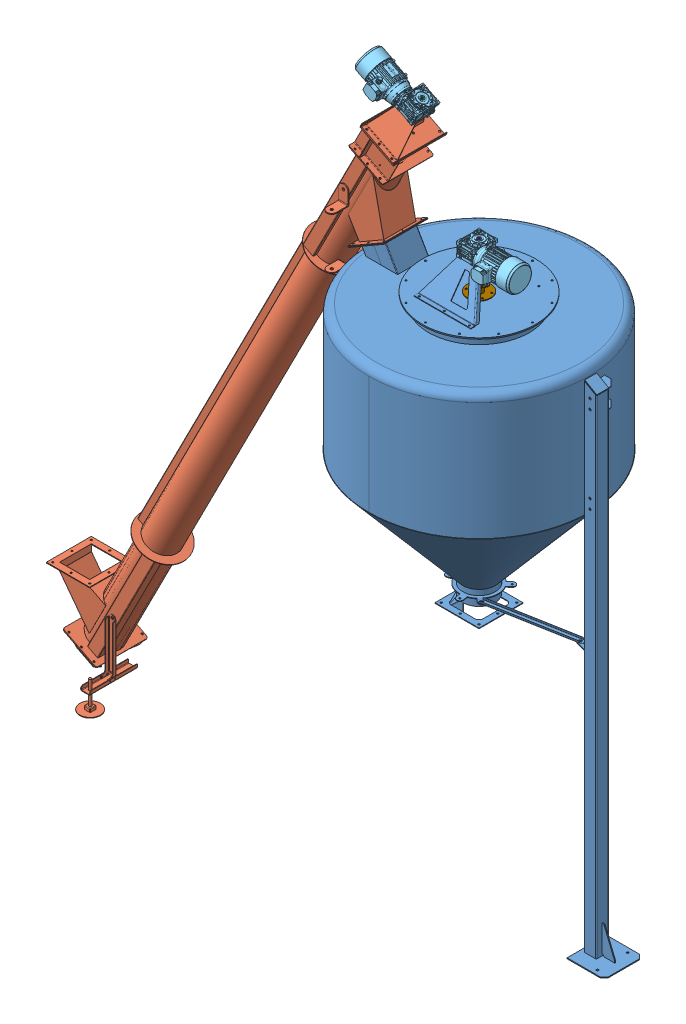
SolidWorks assembly Собираемость ШН+ЕМК ЗАГР, configuration _00. Lengths in mm.
Overall size (3529.98 4401.95 1403.05).
16 component instances, 14 part files, 35 mates.
Components (placement in the parent):
- Емкость Разгр СВД-1: Емкость Разгр СВД [_00] at origin size (1682.69 3474.3 1403.05)
- Шнек Шнек РАЗГ СВД-1: Шнек Шнек РАЗГ СВД [_00] at (-2375.6474 197.619 0) size (2261.6 4104.57 500)
- UCF205-1: UCF205 [_00] at (-2445.5619 60.404 0) x (-0.45399 -0.891007 0) z (0 0 1) size (35.7 95 95) (hidden)
- UCF205-2: UCF205 [_00] at (-485.2309 3907.7702 0) x (-0.45399 -0.891007 0) z (0 0 1) size (35.7 95 95)
- Спираль РАЗГ СВД-1: Спираль РАЗГ СВД [_00] at (-2462.8135 26.5458 0) x (0.45399 0.891007 0) z (0 0 1) size (4841.57 194.01 194.56)
- Редуктор-1: Редуктор [_00] at (-530.0231 3819.8606 0) x (-0.45399 -0.891007 0) z (0 0 1) size (160.29 372.5 231.5)
- 2.377.06.00.01_Вал-1: 2.377.06.00.01_Вал [_00] at (-359.2486 4155.0245 0) x (-0.45399 -0.891007 0) z (0 0 1) size (160 25 25)
- 2.377.06.00.02_Втулка-1: 2.377.06.00.02_Втулка [_00] at (-477.0591 3923.8083 0) x (0.45399 0.891007 0) z (0 0 1) size (127 34 34)
- Редуктор-2: Редуктор [_00] at (0 3843.6632 0) x (0 1 0) z (0 0 1) size (160.29 372.5 231.5)
- 2.377.06.00.03_Вал-1: 2.377.06.00.03_Вал [_00] at (0 3559.5 0) x (0 -1 0) z (-0.877345 0 0.479861) size (360 25 25)
- Сальник ДЕТ-1: Сальник ДЕТ [_00] at (15.0304 3266 705.4055) x (0 1 0) z (-0.506034 0 0.862514) size (88 150 150)
- 2.377.06.00.04_Труба-1: 2.377.06.00.04_Труба [_00] at (0 1662 0) x (0.479861 0 0.877345) z (-0.877345 0 0.479861) size (30 1585 30)
- 2.377.06.00.05_Втулка-1: 2.377.06.00.05_Втулка [_00] at (0 1652 0) size (30 30 30)
- 2.377.06.00.06_Штырь-1: 2.377.06.00.06_Штырь [_00] at (175.4689 1867 -95.9722) x (0.479861 0 0.877345) z (-0.877345 0 0.479861) size (12 12 400)
- 2.377.06.00.07_Штырь-1: 2.377.06.00.07_Штырь [_00] at (-50.3854 1747 -92.1212) x (0.877345 0 -0.479861) z (0.479861 0 0.877345) size (12 12 210)
- Винт М6х16 DIN7991-1: Винт М6х16 DIN7991 [По умолчанию] at (-2439.5238 72.2544 17.8) x (0 0 1) z (-1 0 0) size (16 13.4 13.4)
Mates (geometry in assembly coordinates):
- Совпадение1: coincident anti-aligned: plane of Емкость Разгр СВД-1 through (-692 3237.7 140) normal (-0.5 0.866025 0); plane of Шнек Шнек РАЗГ СВД-1 through (-692 3237.7 140) normal (0.5 -0.866025 0)
- Концентричный1: concentric anti-aligned: cylinder of Емкость Разгр СВД-1 through (-479.1539 3349.0397 120) axis (-0.5 0.866025 0) radius 5.5; cylinder of Шнек Шнек РАЗГ СВД-1 through (-487.1539 3362.8962 120) axis (0.5 -0.866025 0) radius 5.5
- Концентричный2: concentric anti-aligned: cylinder of Емкость Разгр СВД-1 through (-669.6795 3239.0397 120) axis (-0.5 0.866025 0) radius 5.5; cylinder of Шнек Шнек РАЗГ СВД-1 through (-677.6795 3252.8962 120) axis (0.5 -0.866025 0) radius 5.5
- Совпадение4: coincident anti-aligned: plane of Шнек Шнек РАЗГ СВД-1 through (-2338.6411 5.9252 -60) normal (-0.45399 -0.891007 0); plane of UCF205-1 through (-2487.8847 81.9686 47.5) normal (0.45399 0.891007 0)
- Концентричный5: concentric aligned: cylinder of Шнек Шнек РАЗГ СВД-1 through (-2443.2919 64.8591 0) axis (-0.45399 -0.891007 0) radius 25; cylinder of UCF205-1 through (-2461.7694 28.5951 0) axis (-0.45399 -0.891007 0) radius 12.5
- Концентричный6: concentric anti-aligned: cylinder of Шнек Шнек РАЗГ СВД-1 through (-2474.4772 80.7487 -35) axis (-0.45399 -0.891007 0) radius 5.5; cylinder of UCF205-1 through (-2483.103 63.8196 -35) axis (0.45399 0.891007 0) radius 6
- Концентричный7: concentric anti-aligned: cylinder of UCF205-1 through (-2461.7694 28.5951 0) axis (-0.45399 -0.891007 0) radius 12.5; cylinder of Спираль РАЗГ СВД-1 through (-2357.4877 233.2593 0) axis (0.45399 0.891007 0) radius 12.5
- Совпадение5: coincident anti-aligned: plane of UCF205-1 through (-2462.8966 67.3286 -18.25) normal (0.45399 0.891007 0); plane of Спираль РАЗГ СВД-1 through (-2457.4713 64.5642 0) normal (-0.45399 -0.891007 0)
- Совпадение6: coincident aligned: plane of Шнек Шнек РАЗГ СВД-1 through (-76.3155 3910.4147 0) normal (0.45399 0.891007 0); plane of Редуктор-1 through (-354.8665 4052.3435 -50.5206) normal (0.45399 0.891007 0)
- Концентричный8: concentric anti-aligned: cylinder of Шнек Шнек РАЗГ СВД-1 through (-403.5126 4068.1514 0) axis (0.45399 0.891007 0) radius 35; cylinder of Редуктор-1 through (-399.8807 4075.2794 0) axis (-0.45399 -0.891007 0) radius 35
- Концентричный9: concentric anti-aligned: cylinder of Шнек Шнек РАЗГ СВД-1 through (-430.2892 4081.7947 30.052) axis (0.45399 0.891007 0) radius 3.5; cylinder of Редуктор-1 through (-426.3501 4089.5255 30.052) axis (-0.45399 -0.891007 0) radius 3.3235
- Концентричный10: concentric aligned: cylinder of Редуктор-1 through (-401.0157 4073.0519 0) axis (0.45399 0.891007 0) radius 12.5; cylinder of 2.377.06.00.01_Вал-1 through (-401.0157 4073.0519 0) axis (0.45399 0.891007 0) radius 12.5
- Совпадение8: coincident aligned: plane of Редуктор-1 through (-418.8367 4082.1322 -20.001) normal (-0.45399 -0.891007 0); plane of 2.377.06.00.01_Вал-1 through (-401.0157 4073.0519 0) normal (-0.45399 -0.891007 0)
- Перпендикулярность2: perpendicular: plane of Спираль РАЗГ СВД-1 through (-485.8185 3918.7317 -97.2781) normal (0.891007 -0.45399 0); plane of 2.377.06.00.01_Вал-1 through (-439.5773 4030.4109 5.5) normal (0 0 -1)
- Совпадение9: coincident aligned: plane of Емкость Разгр СВД-1 through (180 3470 0) normal (0 1 0); plane of Редуктор-2 through (50.446 3470 -50.446) normal (0 1 0)
- Концентричный14: concentric aligned: cylinder of Емкость Разгр СВД-1 through (0 3463.2 0) axis (0 1 0) radius 35.5; cylinder of Редуктор-2 through (0 3557 0) axis (0 1 0) radius 35
- Концентричный15: concentric aligned: cylinder of Емкость Разгр СВД-1 through (30.052 3463.2 30.052) axis (0 1 0) radius 4.5; cylinder of Редуктор-2 through (30.052 3556.3235 30.052) axis (0 1 0) radius 3.3235
- Совпадение11: coincident aligned: plane of Редуктор-2 through (20.001 3559.5 -20.001) normal (0 1 0); plane of 2.377.06.00.03_Вал-1 through (0 3559.5 0) normal (0 1 0)
- Концентричный16: concentric aligned: cylinder of Редуктор-2 through (0 3559.5 0) axis (0 -1 0) radius 12.5; cylinder of 2.377.06.00.03_Вал-1 through (0 3510.3507 0) axis (0 -1 0) radius 12.5
- Концентричный17: concentric aligned: cylinder of Емкость Разгр СВД-1 through (0 3266 0) axis (0 -1 0) radius 360; cylinder of Сальник ДЕТ-1 through (0 3482.132 0) axis (0 -1 0) radius 75
- Совпадение13: coincident anti-aligned: plane of Емкость Разгр СВД-1 through (0 3266 0) normal (0 1 0); plane of Сальник ДЕТ-1 through (0 3266 0) normal (0 -1 0)
- Концентричный18: concentric aligned: cylinder of 2.377.06.00.03_Вал-1 through (0 3510.3507 0) axis (0 -1 0) radius 12.5; cylinder of 2.377.06.00.04_Труба-1 through (0 3247 0) axis (0 -1 0) radius 15
- Концентричный19: concentric aligned: cylinder of 2.377.06.00.03_Вал-1 through (10.9668 3232 -5.9983) axis (-0.877345 0 0.479861) radius 5.5; cylinder of 2.377.06.00.04_Труба-1 through (13.1602 3232 -7.1979) axis (-0.877345 0 0.479861) radius 5.5
- Совпадение14: coincident anti-aligned: plane of 2.377.06.00.04_Труба-1 through (0 1662 0) normal (0 -1 0); plane of 2.377.06.00.05_Втулка-1 through (-15 1662 0) normal (0 1 0)
- Концентричный20: concentric anti-aligned: cylinder of 2.377.06.00.04_Труба-1 through (0 3247 0) axis (0 -1 0) radius 15; cylinder of 2.377.06.00.05_Втулка-1 through (0 1682 0) axis (0 1 0) radius 12.5
- Концентричный21: concentric anti-aligned: cylinder of 2.377.06.00.04_Труба-1 through (-7.1979 1747 -13.1602) axis (0.479861 0 0.877345) radius 6; cylinder of 2.377.06.00.07_Штырь-1 through (50.3854 1747 92.1212) axis (-0.479861 0 -0.877345) radius 6
- Концентричный22: concentric anti-aligned: cylinder of 2.377.06.00.04_Труба-1 through (13.1602 1867 -7.1979) axis (-0.877345 0 0.479861) radius 6; cylinder of 2.377.06.00.06_Штырь-1 through (-175.4689 1867 95.9722) axis (0.877345 0 -0.479861) radius 6
- Симметричный1: symmetric aligned: plane of 2.377.06.00.04_Труба-1 through (0 1662 0) normal (-0.877345 0 0.479861); plane of 2.377.06.00.06_Штырь-1 through (-175.4689 1867 95.9722) normal (-0.877345 0 0.479861); plane of 2.377.06.00.06_Штырь-1 through (175.4689 1867 -95.9722) normal (0.877345 0 -0.479861)
- Симметричный2: symmetric aligned: plane of 2.377.06.00.04_Труба-1 through (0 1662 0) normal (0.479861 0 0.877345); plane of 2.377.06.00.07_Штырь-1 through (50.3854 1747 92.1212) normal (0.479861 0 0.877345); plane of 2.377.06.00.07_Штырь-1 through (-50.3854 1747 -92.1212) normal (-0.479861 0 -0.877345)
- Совпадение15: coincident aligned: cone of Спираль РАЗГ СВД-1 through (-2439.5238 72.2544 14.25) axis (0 0 -1); cone of Винт М6х16 DIN7991-1 through (-2439.5238 72.2544 17.7) axis (0 0 -1)
- Совпадение16: coincident anti-aligned: plane of Шнек Шнек РАЗГ СВД-1 through (-485.2309 3907.7702 0) normal (-0.45399 -0.891007 0); plane of UCF205-2 through (-527.5537 3929.3347 47.5) normal (0.45399 0.891007 0)
- Концентричный23: concentric anti-aligned: cylinder of UCF205-2 through (-501.4384 3875.9613 0) axis (-0.45399 -0.891007 0) radius 12.5; cylinder of Спираль РАЗГ СВД-1 through (-461.6234 3954.1025 0) axis (0.45399 0.891007 0) radius 12.5
- Концентричный24: concentric aligned: cylinder of Шнек Шнек РАЗГ СВД-1 through (-517.6873 3921.165 -35) axis (0.45399 0.891007 0) radius 5.5; cylinder of UCF205-2 through (-522.772 3911.1858 -35) axis (0.45399 0.891007 0) radius 6
- Концентричный25: concentric anti-aligned: cylinder of Спираль РАЗГ СВД-1 through (-461.6234 3954.1025 0) axis (0.45399 0.891007 0) radius 12.5; cylinder of 2.377.06.00.02_Втулка-1 through (-419.4023 4036.9661 0) axis (-0.45399 -0.891007 0) radius 12.75
- Концентричный26: concentric anti-aligned: cylinder of 2.377.06.00.01_Вал-1 through (-439.5773 4030.4109 0) axis (0.891007 -0.45399 0) radius 5.5; cylinder of 2.377.06.00.02_Втулка-1 through (-411.065 4015.8832 0) axis (-0.891007 0.45399 0) radius 4.25
